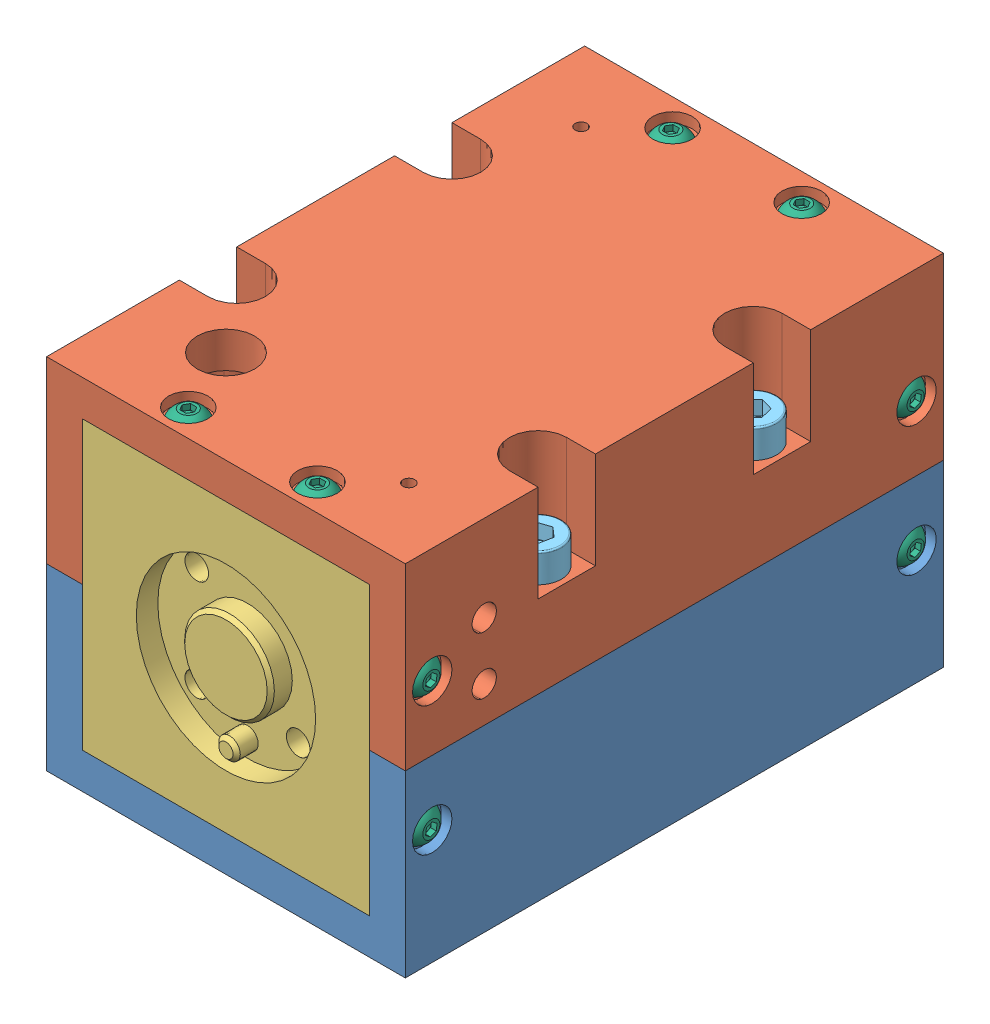
SolidWorks assembly Conjunto, configuration Default. Lengths in mm.
Overall size (100.24 100 190.87).
29 component instances, 8 part files, 58 mates.
Components (placement in the parent):
- Estrutura_bottom-1: Estrutura_bottom [Default] at (-19.0494 -42.1119 38.6623) size (100 50 150)
- Estrutura_top-1: Estrutura_top [Default] at (-19.0494 47.8881 38.6623) x (-1 0 0) z (0 0 1) size (100 50 150)
- Acoplamento_robot_50mm-1: Acoplamento_robot_50mm [Default] at (-19.0494 -2.1119 23.6623) size (80 80 15)
- Acplamento_garra-1: Acplamento_garra [Default] at (-19.0494 -2.1119 -96.3377) size (80 80 102.04)
- Socket Head Cap Screw_ISO-4: Socket Head Cap Screw_ISO [ISO 4762 M8 x 40 --- 28C] at (22.9506 28.8881 -6.3377) x (0 -1 0) z (-0.319372 0 -0.947629) size (48 13 13)
- Socket Head Cap Screw_ISO-5: Socket Head Cap Screw_ISO [ISO 4762 M8 x 40 --- 28C] at (-61.0494 28.8881 -6.3377) x (0 -1 0) z (0.245168 0 0.96948) size (48 13 13)
- Socket Head Cap Screw_ISO-6: Socket Head Cap Screw_ISO [ISO 4762 M8 x 40 --- 28C] at (22.9506 28.8881 -66.3377) x (0 -1 0) z (0.971794 0 -0.235832) size (48 13 13)
- Socket Head Cap Screw_ISO-7: Socket Head Cap Screw_ISO [ISO 4762 M8 x 40 --- 28C] at (-61.0494 28.8881 -66.3377) x (0 -1 0) z (0 0 1) size (48 13 13)
- Socket Button Head Screw_ISO-1: Socket Button Head Screw_ISO [ISO 7380 - M5 x 16 --- 16C] at (-68.7994 15.8881 -103.8377) x (1 0 0) z (0 -0.335428 0.942066) size (18.75 9.5 9.5)
- Socket Button Head Screw_ISO-2: Socket Button Head Screw_ISO [ISO 7380 - M5 x 16 --- 16C] at (-68.7994 -20.1119 -103.8377) size (18.75 9.5 9.5)
- Socket Button Head Screw_ISO-3: Socket Button Head Screw_ISO [ISO 7380 - M5 x 16 --- 16C] at (-68.7994 -20.1119 31.1623) size (18.75 9.5 9.5)
- Socket Button Head Screw_ISO-4: Socket Button Head Screw_ISO [ISO 7380 - M5 x 16 --- 16C] at (-68.7994 15.8881 31.1623) size (18.75 9.5 9.5)
- Socket Button Head Screw_ISO-5: Socket Button Head Screw_ISO [ISO 7380 - M5 x 16 --- 16C] at (30.7006 -20.1119 -103.8377) x (-1 0 0) z (0 -0.924225 -0.381849) size (18.75 9.5 9.5)
- Socket Button Head Screw_ISO-6: Socket Button Head Screw_ISO [ISO 7380 - M5 x 16 --- 16C] at (30.7006 15.8881 31.1623) x (-1 0 0) z (0 -0.924225 -0.381849) size (18.75 9.5 9.5)
- Socket Button Head Screw_ISO-7: Socket Button Head Screw_ISO [ISO 7380 - M5 x 16 --- 16C] at (30.7006 15.8881 -103.8377) x (-1 0 0) z (0 -0.924225 -0.381849) size (18.75 9.5 9.5)
- Socket Button Head Screw_ISO-8: Socket Button Head Screw_ISO [ISO 7380 - M5 x 16 --- 16C] at (30.7006 -20.1119 31.1623) x (-1 0 0) z (0 -0.924225 -0.381849) size (18.75 9.5 9.5)
- Socket Button Head Screw_ISO-9: Socket Button Head Screw_ISO [ISO 7380 - M5 x 16 --- 16C] at (-1.0494 -49.8619 31.1623) x (0 1 0) z (-0.188342 0 0.982104) size (18.75 9.5 9.5)
- Socket Button Head Screw_ISO-10: Socket Button Head Screw_ISO [ISO 7380 - M5 x 16 --- 16C] at (-37.0494 -49.8619 -103.8377) x (0 1 0) z (-0.319462 0 0.947599) size (18.75 9.5 9.5)
- Socket Button Head Screw_ISO-11: Socket Button Head Screw_ISO [ISO 7380 - M5 x 16 --- 16C] at (-1.0494 -49.8619 -103.8377) x (0 1 0) z (0.485773 0 0.874085) size (18.75 9.5 9.5)
- Socket Button Head Screw_ISO-12: Socket Button Head Screw_ISO [ISO 7380 - M5 x 16 --- 16C] at (-37.0494 -49.8619 31.1623) x (0 1 0) z (-0.266822 0 0.963746) size (18.75 9.5 9.5)
- Socket Button Head Screw_ISO-13: Socket Button Head Screw_ISO [ISO 7380 - M5 x 16 --- 16C] at (-1.0494 47.6381 -103.8377) x (0 -1 0) z (0 0 1) size (18.75 9.5 9.5)
- Socket Button Head Screw_ISO-14: Socket Button Head Screw_ISO [ISO 7380 - M5 x 16 --- 16C] at (-37.1275 47.6381 -103.4453) x (0 -1 0) z (0 0 1) size (18.75 9.5 9.5)
- Socket Button Head Screw_ISO-15: Socket Button Head Screw_ISO [ISO 7380 - M5 x 16 --- 16C] at (-37.0494 47.6381 31.1623) x (0 -1 0) z (0 0 1) size (18.75 9.5 9.5)
- Socket Button Head Screw_ISO-16: Socket Button Head Screw_ISO [ISO 7380 - M5 x 16 --- 16C] at (-1.0494 47.6381 31.1623) x (0 -1 0) z (0 0 1) size (18.75 9.5 9.5)
- PCB-1: PCB [Default] at (-19.0494 13.3881 -36.3377) size (66 1.5 80)
- Slotted Cheese Head Screw_ISO-4: Slotted Cheese Head Screw_ISO [ISO 1207 - M3 x 8 --- 8C] at (10.4506 11.3881 -66.3377) x (0 1 0) z (0.99688 0 -0.078934) size (10.01 5.5 5.5)
- Slotted Cheese Head Screw_ISO-1: Slotted Cheese Head Screw_ISO [ISO 1207 - M3 x 8 --- 8C] at (10.4506 11.3881 -6.3377) x (0 1 0) z (-0.0255 0 0.999675) size (10.01 5.5 5.5)
- Slotted Cheese Head Screw_ISO-2: Slotted Cheese Head Screw_ISO [ISO 1207 - M3 x 8 --- 8C] at (-48.5494 11.3881 -66.3377) x (0 1 0) z (0.247102 0 -0.96899) size (10.01 5.5 5.5)
- Slotted Cheese Head Screw_ISO-3: Slotted Cheese Head Screw_ISO [ISO 1207 - M3 x 8 --- 8C] at (-48.5494 11.3881 -6.3377) x (0 1 0) z (0.728633 0 -0.684905) size (10.01 5.5 5.5)
Mates (geometry in assembly coordinates):
- Concentric7: concentric anti-aligned: cylinder of PCB-1 through (-48.5494 14.8881 -6.3377) axis (0 1 0) radius 1.75; cylinder of Estrutura_top-1 through (-48.5494 14.8881 -6.3377) axis (0 -1 0) radius 1.25
- Concentric8: concentric anti-aligned: cylinder of PCB-1 through (10.4506 14.8881 -66.3377) axis (0 1 0) radius 1.75; cylinder of Estrutura_top-1 through (10.4506 14.8881 -66.3377) axis (0 -1 0) radius 1.25
- Coincident7: coincident anti-aligned: plane of PCB-1 through (13.9506 14.8881 3.6623) normal (0 1 0); plane of Estrutura_top-1 through (16.9506 14.8881 -59.6294) normal (0 -1 0)
- Concentric9: concentric aligned: cylinder of Slotted Cheese Head Screw_ISO-4 through (10.4506 -14.0119 -66.3377) axis (0 -1 0) radius 1.5; cylinder of Estrutura_top-1 through (10.4506 14.8881 -66.3377) axis (0 -1 0) radius 1.25
- Concentric10: concentric aligned: cylinder of Slotted Cheese Head Screw_ISO-2 through (-48.5494 -14.0119 -66.3377) axis (0 -1 0) radius 1.5; cylinder of Estrutura_top-1 through (-48.5494 14.8881 -66.3377) axis (0 -1 0) radius 1.25
- Concentric11: concentric aligned: cylinder of Slotted Cheese Head Screw_ISO-3 through (-48.5494 -14.0119 -6.3377) axis (0 -1 0) radius 1.5; cylinder of Estrutura_top-1 through (-48.5494 14.8881 -6.3377) axis (0 -1 0) radius 1.25
- Concentric12: concentric aligned: cylinder of Slotted Cheese Head Screw_ISO-1 through (10.4506 -14.0119 -6.3377) axis (0 -1 0) radius 1.5; cylinder of Estrutura_top-1 through (10.4506 14.8881 -6.3377) axis (0 -1 0) radius 1.25
- Coincident8: coincident anti-aligned: plane of PCB-1 through (13.9506 13.3881 3.6623) normal (0 -1 0); plane of Slotted Cheese Head Screw_ISO-2 through (-47.0959 13.3881 -65.967) normal (0 1 0)
- Coincident9: coincident anti-aligned: plane of PCB-1 through (13.9506 13.3881 3.6623) normal (0 -1 0); plane of Slotted Cheese Head Screw_ISO-4 through (10.569 13.3881 -64.8423) normal (0 1 0)
- Coincident10: coincident anti-aligned: plane of PCB-1 through (13.9506 13.3881 3.6623) normal (0 -1 0); plane of Slotted Cheese Head Screw_ISO-1 through (8.9511 13.3881 -6.3759) normal (0 1 0)
- Coincident11: coincident anti-aligned: plane of PCB-1 through (13.9506 13.3881 3.6623) normal (0 -1 0); plane of Slotted Cheese Head Screw_ISO-3 through (-47.5221 13.3881 -5.2447) normal (0 1 0)
- Concentric13: concentric aligned: cylinder of Estrutura_bottom-1 through (-61.0494 -2.1119 -6.3377) axis (0 1 0) radius 3.4; cylinder of Estrutura_top-1 through (-61.0494 20.8881 -6.3377) axis (0 1 0) radius 4
- Concentric14: concentric aligned: circle of Estrutura_bottom-1; cylinder of Estrutura_top-1 through (22.9506 20.8881 -66.3377) axis (0 1 0) radius 4
- Coincident12: coincident anti-aligned: plane of Estrutura_bottom-1 through (20.9506 -2.1119 38.6623) normal (0 1 0); plane of Estrutura_top-1 through (20.9506 -2.1119 -111.3377) normal (0 -1 0)
- Concentric20: concentric aligned: cylinder of Estrutura_top-1 through (-1.0494 47.8881 -103.8377) axis (0 1 0) radius 2.75; cylinder of Acplamento_garra-1 through (-1.0494 37.8881 -103.8377) axis (0 1 0) radius 2.1
- Concentric21: concentric aligned: cylinder of Estrutura_top-1 through (30.9506 15.8881 -103.8377) axis (1 0 0) radius 2.75; cylinder of Acplamento_garra-1 through (20.9506 15.8881 -103.8377) axis (1 0 0) radius 2.1
- Concentric22: concentric aligned: cylinder of Estrutura_top-1 through (30.9506 15.8881 31.1623) axis (1 0 0) radius 2.75; cylinder of Acoplamento_robot_50mm-1 through (20.9506 15.8881 31.1623) axis (1 0 0) radius 2.1
- Concentric23: concentric aligned: cylinder of Estrutura_top-1 through (-37.0494 47.8881 31.1623) axis (0 1 0) radius 2.75; cylinder of Acoplamento_robot_50mm-1 through (-37.0494 37.8881 31.1623) axis (0 1 0) radius 2.1
- Concentric24: concentric aligned: cylinder of Estrutura_top-1 through (-61.0494 20.8881 -6.3377) axis (0 1 0) radius 4; cylinder of Socket Head Cap Screw_ISO-5 through (-61.0494 60.6381 -6.3377) axis (0 1 0) radius 4
- Concentric25: concentric aligned: cylinder of Estrutura_top-1 through (22.9506 20.8881 -6.3377) axis (0 1 0) radius 4; cylinder of Socket Head Cap Screw_ISO-4 through (22.9506 60.6381 -6.3377) axis (0 1 0) radius 4
- Concentric26: concentric aligned: cylinder of Estrutura_top-1 through (22.9506 20.8881 -66.3377) axis (0 1 0) radius 4; cylinder of Socket Head Cap Screw_ISO-6 through (22.9506 60.6381 -66.3377) axis (0 1 0) radius 4
- Concentric27: concentric aligned: cylinder of Estrutura_top-1 through (-61.0494 20.8881 -66.3377) axis (0 1 0) radius 4; cylinder of Socket Head Cap Screw_ISO-7 through (-61.0494 60.6381 -66.3377) axis (0 1 0) radius 4
- Coincident17: coincident anti-aligned: plane of Estrutura_top-1 through (-61.0494 20.8881 -6.3377) normal (0 1 0); plane of Socket Head Cap Screw_ISO-5 through (-54.7478 20.8881 -7.9312) normal (0 -1 0)
- Coincident18: coincident anti-aligned: plane of Estrutura_top-1 through (-61.0494 20.8881 -66.3377) normal (0 1 0); plane of Socket Head Cap Screw_ISO-7 through (-54.5494 20.8881 -66.3377) normal (0 -1 0)
- Coincident19: coincident anti-aligned: plane of Estrutura_top-1 through (22.9506 20.8881 -66.3377) normal (0 1 0); plane of Socket Head Cap Screw_ISO-6 through (21.4177 20.8881 -72.6543) normal (0 -1 0)
- Coincident20: coincident anti-aligned: plane of Estrutura_top-1 through (22.9506 20.8881 -6.3377) normal (0 1 0); plane of Socket Head Cap Screw_ISO-4 through (16.791 20.8881 -4.2617) normal (0 -1 0)
- Concentric28: concentric aligned: cylinder of Acoplamento_robot_50mm-1 through (-1.0494 37.8881 31.1623) axis (0 1 0) radius 2.1; cylinder of Socket Button Head Screw_ISO-16 through (-1.0494 47.6381 31.1623) axis (0 1 0) radius 2.5
- Concentric29: concentric aligned: cylinder of Acoplamento_robot_50mm-1 through (-37.0494 37.8881 31.1623) axis (0 1 0) radius 2.1; cylinder of Socket Button Head Screw_ISO-15 through (-37.0494 47.6381 31.1623) axis (0 1 0) radius 2.5
- Tangent2: tangent aligned: cylinder of Socket Button Head Screw_ISO-14 through (-37.1275 47.6381 -103.4453) axis (0 1 0) radius 2.5; cylinder of Acplamento_garra-1 through (-37.0494 37.8881 -103.8377) axis (0 1 0) radius 2.1
- Concentric30: concentric aligned: cylinder of Acplamento_garra-1 through (-1.0494 37.8881 -103.8377) axis (0 1 0) radius 2.1; cylinder of Socket Button Head Screw_ISO-13 through (-1.0494 47.6381 -103.8377) axis (0 1 0) radius 2.5
- Coincident21: coincident anti-aligned: plane of Estrutura_top-1 through (-3.7994 44.8881 -103.8377) normal (0 1 0); plane of Socket Button Head Screw_ISO-13 through (1.4506 44.8881 -103.8377) normal (0 -1 0)
- Coincident22: coincident anti-aligned: plane of Estrutura_top-1 through (-39.7994 44.8881 -103.8377) normal (0 1 0); plane of Socket Button Head Screw_ISO-14 through (-34.6275 44.8881 -103.4453) normal (0 -1 0)
- Coincident23: coincident anti-aligned: plane of Estrutura_top-1 through (-39.7994 44.8881 31.1623) normal (0 1 0); plane of Socket Button Head Screw_ISO-15 through (-34.5494 44.8881 31.1623) normal (0 -1 0)
- Coincident24: coincident anti-aligned: plane of Estrutura_top-1 through (-3.7994 44.8881 31.1623) normal (0 1 0); plane of Socket Button Head Screw_ISO-16 through (1.4506 44.8881 31.1623) normal (0 -1 0)
- Concentric31: concentric aligned: cylinder of Acplamento_garra-1 through (20.9506 -20.1119 -103.8377) axis (1 0 0) radius 2.1; cylinder of Socket Button Head Screw_ISO-5 through (30.7006 -20.1119 -103.8377) axis (1 0 0) radius 2.5
- Concentric32: concentric aligned: cylinder of Acplamento_garra-1 through (20.9506 15.8881 -103.8377) axis (1 0 0) radius 2.1; cylinder of Socket Button Head Screw_ISO-7 through (30.7006 15.8881 -103.8377) axis (1 0 0) radius 2.5
- Concentric33: concentric aligned: cylinder of Acoplamento_robot_50mm-1 through (20.9506 -20.1119 31.1623) axis (1 0 0) radius 2.1; cylinder of Socket Button Head Screw_ISO-8 through (30.7006 -20.1119 31.1623) axis (1 0 0) radius 2.5
- Concentric34: concentric aligned: cylinder of Acoplamento_robot_50mm-1 through (20.9506 15.8881 31.1623) axis (1 0 0) radius 2.1; cylinder of Socket Button Head Screw_ISO-6 through (30.7006 15.8881 31.1623) axis (1 0 0) radius 2.5
- Coincident25: coincident anti-aligned: plane of Estrutura_top-1 through (27.9506 13.1381 31.1623) normal (1 0 0); plane of Socket Button Head Screw_ISO-6 through (27.9506 16.8427 28.8518) normal (-1 0 0)
- Coincident26: coincident anti-aligned: plane of Estrutura_bottom-1 through (27.9506 -17.3619 31.1623) normal (1 0 0); plane of Socket Button Head Screw_ISO-8 through (27.9506 -19.1573 28.8518) normal (-1 0 0)
- Coincident27: coincident anti-aligned: plane of Estrutura_bottom-1 through (27.9506 -17.3619 -103.8377) normal (1 0 0); plane of Socket Button Head Screw_ISO-5 through (27.9506 -19.1573 -106.1482) normal (-1 0 0)
- Coincident28: coincident anti-aligned: plane of Estrutura_top-1 through (27.9506 13.1381 -103.8377) normal (1 0 0); plane of Socket Button Head Screw_ISO-7 through (27.9506 16.8427 -106.1482) normal (-1 0 0)
- Concentric35: concentric aligned: cylinder of Acoplamento_robot_50mm-1 through (-59.0494 15.8881 31.1623) axis (-1 0 0) radius 2.1; cylinder of Socket Button Head Screw_ISO-4 through (-68.7994 15.8881 31.1623) axis (-1 0 0) radius 2.5
- Concentric36: concentric aligned: cylinder of Acoplamento_robot_50mm-1 through (-59.0494 -20.1119 31.1623) axis (-1 0 0) radius 2.1; cylinder of Socket Button Head Screw_ISO-3 through (-68.7994 -20.1119 31.1623) axis (-1 0 0) radius 2.5
- Concentric37: concentric aligned: cylinder of Acplamento_garra-1 through (-59.0494 -20.1119 -103.8377) axis (-1 0 0) radius 2.1; cylinder of Socket Button Head Screw_ISO-2 through (-68.7994 -20.1119 -103.8377) axis (-1 0 0) radius 2.5
- Concentric38: concentric aligned: cylinder of Acplamento_garra-1 through (-59.0494 15.8881 -103.8377) axis (-1 0 0) radius 2.1; cylinder of Socket Button Head Screw_ISO-1 through (-68.7994 15.8881 -103.8377) axis (-1 0 0) radius 2.5
- Coincident29: coincident anti-aligned: plane of Estrutura_bottom-1 through (-66.0494 -17.3619 -103.8377) normal (-1 0 0); plane of Socket Button Head Screw_ISO-2 through (-66.0494 -17.6119 -103.8377) normal (1 0 0)
- Coincident30: coincident anti-aligned: plane of Estrutura_bottom-1 through (-66.0494 -17.3619 31.1623) normal (-1 0 0); plane of Socket Button Head Screw_ISO-3 through (-66.0494 -17.6119 31.1623) normal (1 0 0)
- Coincident31: coincident anti-aligned: plane of Estrutura_top-1 through (-66.0494 13.1381 31.1623) normal (-1 0 0); plane of Socket Button Head Screw_ISO-4 through (-66.0494 18.3881 31.1623) normal (1 0 0)
- Coincident32: coincident anti-aligned: plane of Estrutura_top-1 through (-66.0494 13.1381 -103.8377) normal (-1 0 0); plane of Socket Button Head Screw_ISO-1 through (-66.0494 18.2432 -102.9991) normal (1 0 0)
- Concentric39: concentric aligned: cylinder of Acoplamento_robot_50mm-1 through (-1.0494 -42.1119 31.1623) axis (0 -1 0) radius 2.1; cylinder of Socket Button Head Screw_ISO-9 through (-1.0494 -49.8619 31.1623) axis (0 -1 0) radius 2.5
- Concentric40: concentric aligned: cylinder of Acoplamento_robot_50mm-1 through (-37.0494 -42.1119 31.1623) axis (0 -1 0) radius 2.1; cylinder of Socket Button Head Screw_ISO-12 through (-37.0494 -49.8619 31.1623) axis (0 -1 0) radius 2.5
- Concentric41: concentric aligned: cylinder of Acplamento_garra-1 through (-1.0494 -42.1119 -103.8377) axis (0 -1 0) radius 2.1; cylinder of Socket Button Head Screw_ISO-11 through (-1.0494 -49.8619 -103.8377) axis (0 -1 0) radius 2.5
- Concentric42: concentric aligned: cylinder of Acplamento_garra-1 through (-37.0494 -42.1119 -103.8377) axis (0 -1 0) radius 2.1; cylinder of Socket Button Head Screw_ISO-10 through (-37.0494 -49.8619 -103.8377) axis (0 -1 0) radius 2.5
- Coincident33: coincident anti-aligned: plane of Estrutura_bottom-1 through (1.7006 -47.1119 31.1623) normal (0 -1 0); plane of Socket Button Head Screw_ISO-9 through (-3.5047 -47.1119 30.6915) normal (0 1 0)
- Coincident34: coincident anti-aligned: plane of Estrutura_bottom-1 through (-34.2994 -47.1119 31.1623) normal (0 -1 0); plane of Socket Button Head Screw_ISO-12 through (-39.4588 -47.1119 30.4953) normal (0 1 0)
- Coincident35: coincident anti-aligned: plane of Estrutura_bottom-1 through (1.7006 -47.1119 -103.8377) normal (0 -1 0); plane of Socket Button Head Screw_ISO-11 through (-3.2346 -47.1119 -102.6232) normal (0 1 0)
- Coincident36: coincident anti-aligned: plane of Estrutura_bottom-1 through (-34.2994 -47.1119 -103.8377) normal (0 -1 0); plane of Socket Button Head Screw_ISO-10 through (-39.4184 -47.1119 -104.6363) normal (0 1 0)
